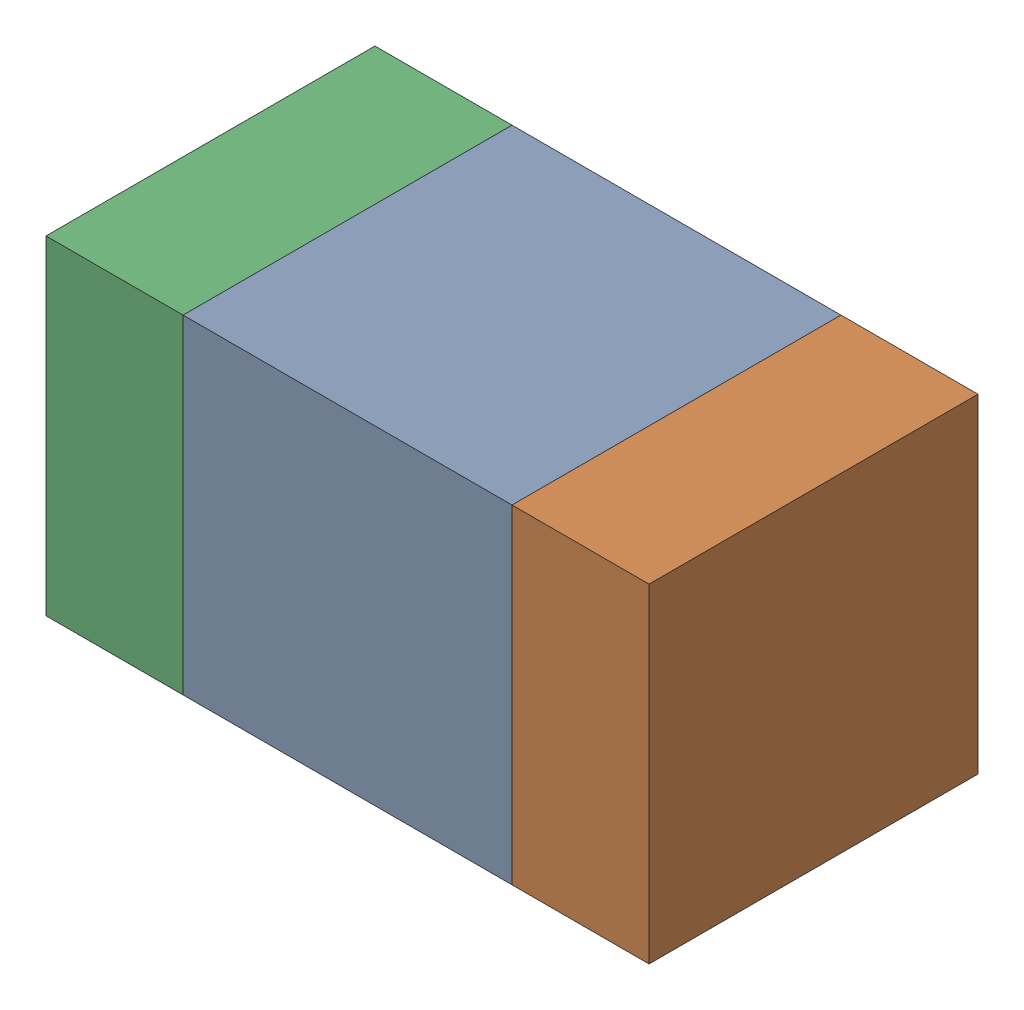
SolidWorks assembly C427PCB, configuration Default. Lengths in mm.
Overall size (1.1 0.6 0.6).
6 component instances, 2 part files, 0 mates.
Components (placement in the parent):
- 761606048-1: 761606048 [Default] at (115.1 92.9 -2.2638) size (0.6 0.6 0.6)
  - Extruded_9-1: Extruded_9 [Default] at origin size (0.6 0.6 0.6)
- 854785160-1: 854785160 [Default] at (115.525 92.9 -2.2638) size (0.25 0.6 0.6)
  - Extruded_19-1: Extruded_19 [Default] at origin size (0.25 0.6 0.6)
- 854785160-2: 854785160 [Default] at (114.675 92.9 -2.2638) size (0.25 0.6 0.6)
  - Extruded_19-1: Extruded_19 [Default] at origin size (0.25 0.6 0.6)
